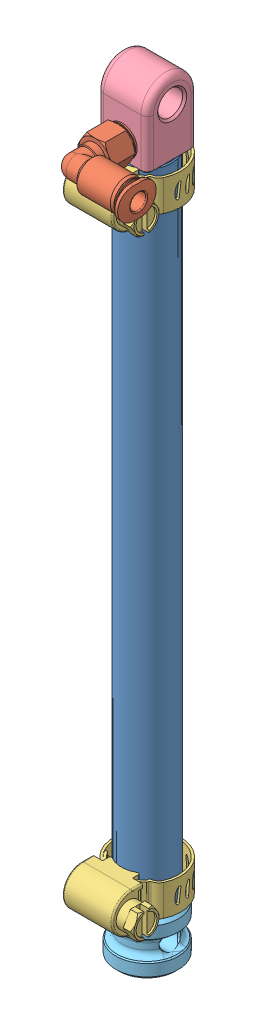
SolidWorks assembly AARL_QR_PN_PA_FL_WR_EX-Extensor, configuration Default. Lengths in mm.
Overall size (24.22 196.85 31.28).
6 component instances, 5 part files, 15 mates.
Components (placement in the parent):
- AARL_QR_PN_PA_FL_WR_EX_001-1: AARL_QR_PN_PA_FL_WR_EX_001 [Resting] at origin size (12.7 165.1 12.7)
- AARL_Puppy_18_02_57_010-QSML-M3-4-1: AARL_Puppy_18_02_57_010-QSML-M3-4 [Default] at (0 87.3125 17.85) x (1 0 0) z (0 0 -1) size (20.32 8 18.9)
- AARL_Puppy_18_02_57_011-5388K140_Hose-Clamp-1: AARL_Puppy_18_02_57_011-5388K140_Hose-Clamp [5388K14] at (0 77.597 0) x (1 0 0) z (0 -1 0) size (19.43 23.71 9.91)
- AARL_Puppy_18_02_57_011-5388K140_Hose-Clamp-2: AARL_Puppy_18_02_57_011-5388K140_Hose-Clamp [5388K14] at (0 -77.597 0) x (1 0 0) z (0 -1 0) size (19.43 23.71 9.91)
- AARL_QR_PN_EP_001-1: AARL_QR_PN_EP_001 [Default] at (0 95.25 0) x (0 0 1) z (-1 0 0) size (12.7 31.75 12.7)
- AARL_QR_PN_EP_002-1: AARL_QR_PN_EP_002 [Default] at (0 -82.55 0) x (-1 0 0) z (0 0 1) size (15.88 25.4 15.88)
Mates (geometry in assembly coordinates):
- Concentric1: concentric aligned: cylinder of AARL_QR_PN_PA_FL_WR_EX_001-1 through (0 11.6086 0) axis (0 1 0) radius 4.7625; cylinder of AARL_QR_PN_EP_001-1 through (0 104.794 0) axis (0 1 0) radius 4.3656
- Parallel1: parallel aligned: plane of AARL_QR_PN_EP_001-1 through (-6.35 82.55 6.35) normal (0 0 1)
- Coincident2: coincident anti-aligned: plane of AARL_QR_PN_PA_FL_WR_EX_001-1 through (4.7625 82.55 0) normal (0 1 0); plane of AARL_QR_PN_EP_001-1 through (-6.35 82.55 -6.35) normal (0 -1 0)
- Concentric2: concentric anti-aligned: cylinder of AARL_QR_PN_PA_FL_WR_EX_001-1 through (0 11.6086 0) axis (0 1 0) radius 4.7625; cylinder of AARL_QR_PN_EP_002-1 through (0 -90.2877 0) axis (0 -1 0) radius 4.3656
- Coincident3: coincident anti-aligned: plane of AARL_QR_PN_PA_FL_WR_EX_001-1 through (6.35 -82.55 0) normal (0 -1 0); plane of AARL_QR_PN_EP_002-1 through (-4.3656 -82.55 0) normal (0 1 0)
- Parallel2: parallel anti-aligned: cylinder of AARL_QR_PN_EP_001-1 through (-6.35 95.25 0) axis (1 0 0) radius 3.175; cylinder of AARL_QR_PN_EP_002-1 through (7.9375 -88.9 0) axis (-1 0 0) radius 2.3813
- Concentric4: concentric aligned: cylinder of AARL_Puppy_18_02_57_010-QSML-M3-4-1 through (0 87.3125 6.35) axis (0 0 1) radius 1.5; cylinder of AARL_QR_PN_EP_001-1 through (0 87.3125 6.35) axis (0 0 1) radius 2.0193
- Parallel3: parallel anti-aligned: plane of AARL_Puppy_18_02_57_010-QSML-M3-4-1 through (-2.3094 91.3125 13.4056) normal (0 1 0); plane of AARL_QR_PN_EP_001-1 through (-6.35 82.55 -6.35) normal (0 -1 0)
- Coincident5: coincident anti-aligned: plane of AARL_Puppy_18_02_57_010-QSML-M3-4-1 through (0 87.3125 6.35) normal (0 0 -1); plane of AARL_QR_PN_EP_001-1 through (-6.35 82.55 6.35) normal (0 0 1)
- Concentric5: concentric aligned: cylinder of AARL_QR_PN_PA_FL_WR_EX_001-1 through (0 11.6086 0) axis (0 1 0) radius 6.35; cylinder of AARL_Puppy_18_02_57_011-5388K140_Hose-Clamp-1 through (0 73.6283 0) axis (0 1 0) radius 7.9375
- Coincident6: coincident aligned: plane of AARL_Puppy_18_02_57_011-5388K140_Hose-Clamp-1 through (6.35 77.597 10.2337) normal (1 0 0); plane of AARL_QR_PN_EP_001-1 through (6.35 95.25 0) normal (1 0 0)
- Coincident7: coincident anti-aligned: plane of AARL_Puppy_18_02_57_011-5388K140_Hose-Clamp-1 through (0 82.55 0) normal (0 1 0); plane of AARL_QR_PN_EP_001-1 through (-6.35 82.55 -6.35) normal (0 -1 0)
- Concentric6: concentric aligned: cylinder of AARL_QR_PN_PA_FL_WR_EX_001-1 through (0 11.6086 0) axis (0 1 0) radius 6.35; cylinder of AARL_Puppy_18_02_57_011-5388K140_Hose-Clamp-2 through (0 -81.5658 0) axis (0 1 0) radius 7.9375
- Coincident8: coincident aligned: plane of AARL_Puppy_18_02_57_011-5388K140_Hose-Clamp-1 through (6.35 77.597 10.2337) normal (1 0 0); plane of AARL_Puppy_18_02_57_011-5388K140_Hose-Clamp-2 through (6.35 -77.597 10.2337) normal (1 0 0)
- Coincident9: coincident anti-aligned: plane of AARL_Puppy_18_02_57_011-5388K140_Hose-Clamp-2 through (0 -82.55 0) normal (0 -1 0); plane of AARL_QR_PN_EP_002-1 through (-4.3656 -82.55 0) normal (0 1 0)
